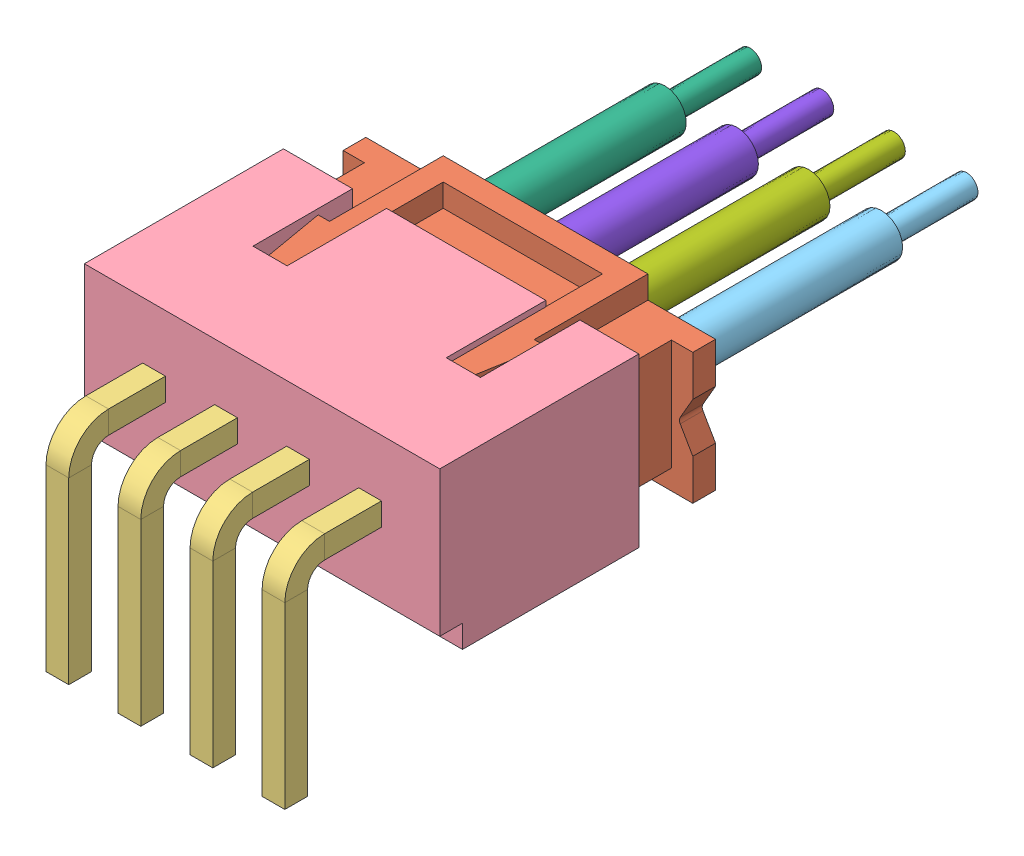
SolidWorks assembly Assem1, configuration Default. Lengths in mm.
Overall size (12.5 9.9 24.38).
14 component instances, 8 part files, 33 mates.
Components (placement in the parent):
- Part1-1: Part1 [Default] at (-22.4316 28.4512 13.4091) x (1 0 0) z (0 1 0) size (1.8 6 3.23)
- Part1-2: Part1 [Default] at (-19.8983 28.4512 13.4091) x (1 0 0) z (0 1 0) size (1.8 6 3.23)
- Part1-3: Part1 [Default] at (-17.3666 28.4512 13.4091) x (1 0 0) z (0 1 0) size (1.8 6 3.23)
- Part1-4: Part1 [Default] at (-14.8316 28.4512 13.4091) x (1 0 0) z (0 1 0) size (1.8 6 3.23)
- JST - XH MALE 4 pin-1: JST - XH MALE 4 pin [Default] at (-18.6316 28.1012 7.0891) size (12.3 5.4 8.4)
- Part3-1: Part3 [Default] at (-22.4316 28.8512 19.0891) x (0 0 1) z (-1 0 0) size (9.7 7.9 0.8)
- Part3-2: Part3 [Default] at (-19.8983 28.8512 19.0891) x (0 0 1) z (-1 0 0) size (9.7 7.9 0.8)
- Part3-3: Part3 [Default] at (-14.8316 28.8512 19.0891) x (0 0 1) z (-1 0 0) size (9.7 7.9 0.8)
- Part3-4: Part3 [Default] at (-17.3649 28.8512 19.0891) x (0 0 1) z (-1 0 0) size (9.7 7.9 0.8)
- Part2-2: Part2 [Default] at (-18.6316 28.3012 9.0891) x (-1 0 0) z (0 1 0) size (12.5 7 5.9)
- Part4-1: Part4 [Default] at (-14.8314 28.1603 -1.8919) size (1.5 1.5 16)
- Part5-1: Part5 [Default] at (-22.4415 28.1513 -1.8901) size (1.5 1.5 16)
- Part8-1: Part8 [Default] at (-17.3787 28.1397 -1.8836) size (1.5 1.5 16)
- Part7-1: Part7 [Default] at (-19.905 28.154 -1.8924) size (1.5 1.5 16)
Mates (geometry in assembly coordinates):
- Width1: width anti-aligned: plane of Part1-1 through (-21.5316 27.3012 11.3091) normal (1 0 0); plane of Part1-1 through (-23.3316 27.3012 11.3091) normal (-1 0 0); plane of JST - XH MALE 4 pin-1 through (-21.3316 29.8512 13.7891) normal (-1 0 0); plane of JST - XH MALE 4 pin-1 through (-23.5316 29.8512 13.7891) normal (1 0 0)
- Width2: width anti-aligned: plane of Part1-1 through (-23.3316 27.3012 11.3091) normal (0 -1 0); plane of Part1-1 through (-23.3316 29.6012 11.3091) normal (0 1 0); plane of JST - XH MALE 4 pin-1 through (-22.0316 27.0512 13.7891) normal (0 1 0); plane of JST - XH MALE 4 pin-1 through (-23.5316 29.8512 13.7891) normal (0 -1 0)
- Width3: width anti-aligned: plane of Part1-2 through (-20.7983 27.3012 11.3091) normal (-1 0 0); plane of Part1-2 through (-18.9983 27.3012 11.3091) normal (1 0 0); plane of JST - XH MALE 4 pin-1 through (-20.9983 29.8512 13.7891) normal (1 0 0); plane of JST - XH MALE 4 pin-1 through (-18.7983 29.8512 13.7891) normal (-1 0 0)
- Width4: width anti-aligned: plane of Part1-2 through (-20.7983 27.3012 11.3091) normal (0 -1 0); plane of Part1-2 through (-20.7983 29.6012 11.3091) normal (0 1 0); plane of JST - XH MALE 4 pin-1 through (-20.9983 27.0512 13.7891) normal (0 1 0); plane of JST - XH MALE 4 pin-1 through (-20.9983 29.8512 13.7891) normal (0 -1 0)
- Width5: width anti-aligned: plane of Part1-3 through (-18.2666 27.3012 11.3091) normal (-1 0 0); plane of Part1-3 through (-16.4666 27.3012 11.3091) normal (1 0 0); plane of JST - XH MALE 4 pin-1 through (-18.4683 29.8512 13.7891) normal (1 0 0); plane of JST - XH MALE 4 pin-1 through (-16.2649 29.8512 13.7891) normal (-1 0 0)
- Width6: width anti-aligned: plane of Part1-3 through (-18.2666 27.3012 11.3091) normal (0 -1 0); plane of Part1-3 through (-18.2666 29.6012 11.3091) normal (0 1 0); plane of JST - XH MALE 4 pin-1 through (-16.9649 27.0512 13.7891) normal (0 1 0); plane of JST - XH MALE 4 pin-1 through (-18.4683 29.8512 13.7891) normal (0 -1 0)
- Width7: width anti-aligned: plane of Part1-4 through (-15.7316 27.3012 11.3091) normal (-1 0 0); plane of Part1-4 through (-13.9316 27.3012 11.3091) normal (1 0 0); plane of JST - XH MALE 4 pin-1 through (-15.9316 29.8512 13.7891) normal (1 0 0); plane of JST - XH MALE 4 pin-1 through (-13.7316 29.8512 13.7891) normal (-1 0 0)
- Width8: width anti-aligned: plane of Part1-4 through (-15.7316 27.3012 11.3091) normal (0 -1 0); plane of Part1-4 through (-15.7316 29.6012 11.3091) normal (0 1 0); plane of JST - XH MALE 4 pin-1 through (-14.4316 27.0512 13.7891) normal (0 1 0); plane of JST - XH MALE 4 pin-1 through (-15.9316 29.8512 13.7891) normal (0 -1 0)
- Distance1: distance = 0.38 mm anti-aligned: plane of Part1-1 through (-22.4316 28.4512 13.4091) normal (0 0 1); plane of JST - XH MALE 4 pin-1 through (-18.6316 28.1012 13.7891) normal (0 0 -1)
- Distance2: distance = 0.38 mm anti-aligned: plane of Part1-2 through (-19.8983 28.4512 13.4091) normal (0 0 1); plane of JST - XH MALE 4 pin-1 through (-18.6316 28.1012 13.7891) normal (0 0 -1)
- Distance3: distance = 0.38 mm anti-aligned: plane of Part1-3 through (-17.3666 28.4512 13.4091) normal (0 0 1); plane of JST - XH MALE 4 pin-1 through (-18.6316 28.1012 13.7891) normal (0 0 -1)
- Distance4: distance = 0.38 mm anti-aligned: plane of Part1-4 through (-14.8316 28.4512 13.4091) normal (0 0 1); plane of JST - XH MALE 4 pin-1 through (-18.6316 28.1012 13.7891) normal (0 0 -1)
- Width9: width anti-aligned: plane of ? through (-23.0316 26.3012 14.5891) normal (1 0 0); plane of ? through (-14.2316 26.3012 14.5891) normal (-1 0 0); plane of JST - XH MALE 4 pin-1 through (-24.0316 25.9512 14.0891) normal (-1 0 0); plane of JST - XH MALE 4 pin-1 through (-13.2316 25.9512 14.0891) normal (1 0 0)
- Width10: width anti-aligned: plane of JST - XH MALE 4 pin-1 through (-18.6316 26.3512 7.0891) normal (0 -1 0); plane of JST - XH MALE 4 pin-1 through (-24.0316 30.2512 14.0891) normal (0 1 0); plane of ? through (-14.2316 26.3012 14.5891) normal (0 1 0); plane of ? through (-14.2316 30.3012 14.5891) normal (0 -1 0)
- LimitDistance1: limit distance = 20 mm anti-aligned: plane of JST - XH MALE 4 pin-1 through (-18.6316 28.1012 14.5891) normal (0 0 1); plane of ? through (-18.6316 28.3012 34.5891) normal (0 0 -1)
- Coincident1: coincident anti-aligned: plane of ? through (-21.5816 29.3512 6.5891) normal (1 0 0); plane of Part3-1 through (-21.5816 29.3512 18.5891) normal (-1 0 0)
- Coincident2: coincident anti-aligned: plane of ? through (-21.5816 29.3512 6.5891) normal (0 -1 0); plane of Part3-1 through (-20.7816 29.3512 18.5891) normal (0 1 0)
- Distance6: distance = 0.7 mm aligned: plane of Part3-1 through (-21.1816 28.9512 10.2891) normal (0 0 -1); plane of ? through (-18.6316 28.3012 9.5891) normal (0 0 -1)
- Coincident4: coincident anti-aligned: plane of ? through (-20.2983 29.2512 6.5891) normal (1 0 0); plane of Part3-2 through (-20.2983 29.2512 18.5891) normal (-1 0 0)
- Coincident5: coincident anti-aligned: plane of ? through (-20.2983 29.2512 6.5891) normal (0 -1 0); plane of Part3-2 through (-19.4983 29.2512 18.5891) normal (0 1 0)
- Coincident6: coincident anti-aligned: plane of ? through (-17.7649 29.2512 6.5891) normal (0 -1 0); plane of Part3-4 through (-16.9649 29.2512 18.5891) normal (0 1 0)
- Coincident7: coincident anti-aligned: plane of ? through (-17.7649 29.2512 6.5891) normal (1 0 0); plane of Part3-4 through (-17.7649 29.2512 18.5891) normal (-1 0 0)
- Coincident8: coincident anti-aligned: plane of ? through (-15.2316 29.2512 6.5891) normal (1 0 0); plane of Part3-3 through (-15.2316 29.2512 18.5891) normal (-1 0 0)
- Coincident9: coincident anti-aligned: plane of ? through (-15.2316 29.2512 6.5891) normal (0 -1 0); plane of Part3-3 through (-14.4316 29.2512 18.5891) normal (0 1 0)
- Coincident10: coincident aligned: plane of Part3-1 through (-22.0316 27.8512 19.4891) normal (0 0 1); plane of Part3-2 through (-19.4983 27.8512 19.4891) normal (0 0 1)
- Coincident11: coincident aligned: plane of Part3-2 through (-19.4983 27.8512 19.4891) normal (0 0 1); plane of Part3-4 through (-16.9649 27.8512 19.4891) normal (0 0 1)
- Coincident12: coincident aligned: plane of Part3-3 through (-14.4316 27.8512 19.4891) normal (0 0 1); plane of Part3-4 through (-16.9649 27.8512 19.4891) normal (0 0 1)
- Width11: width anti-aligned: plane of Part2-2 through (-24.1316 26.3012 14.0891) normal (1 0 0); plane of Part2-2 through (-13.1316 26.3012 14.0891) normal (-1 0 0); plane of JST - XH MALE 4 pin-1 through (-24.0316 25.9512 14.0891) normal (-1 0 0); plane of JST - XH MALE 4 pin-1 through (-13.2316 25.9512 14.0891) normal (1 0 0)
- Width12: width anti-aligned: plane of Part2-2 through (-13.1316 30.3012 14.0891) normal (0 -1 0); plane of Part2-2 through (-13.1316 26.3012 14.0891) normal (0 1 0); plane of JST - XH MALE 4 pin-1 through (-24.0316 30.2512 14.0891) normal (0 1 0); plane of JST - XH MALE 4 pin-1 through (-18.6316 26.3512 7.0891) normal (0 -1 0)
- LimitDistance2: limit distance = 0 mm anti-aligned: plane of Part2-2 through (-18.6316 28.3012 14.0891) normal (0 0 -1); plane of JST - XH MALE 4 pin-1 through (-18.6316 28.1012 14.0891) normal (0 0 1)
- Coincident13: coincident anti-aligned: plane of Part3-1 through (-22.0316 29.2512 18.0891) normal (1 0 0); plane of Part2-2 through (-22.0316 29.2512 6.0891) normal (-1 0 0)
- Coincident17: coincident anti-aligned: plane of Part3-1 through (-22.0316 29.2512 18.0891) normal (0 1 0); plane of Part2-2 through (-22.8316 29.2512 6.0891) normal (0 -1 0)
- Distance8: distance = 0.7 mm aligned: plane of Part2-2 through (-18.6316 28.3012 9.0891) normal (0 0 -1); plane of Part3-1 through (-22.4316 28.8512 9.7891) normal (0 0 -1)
